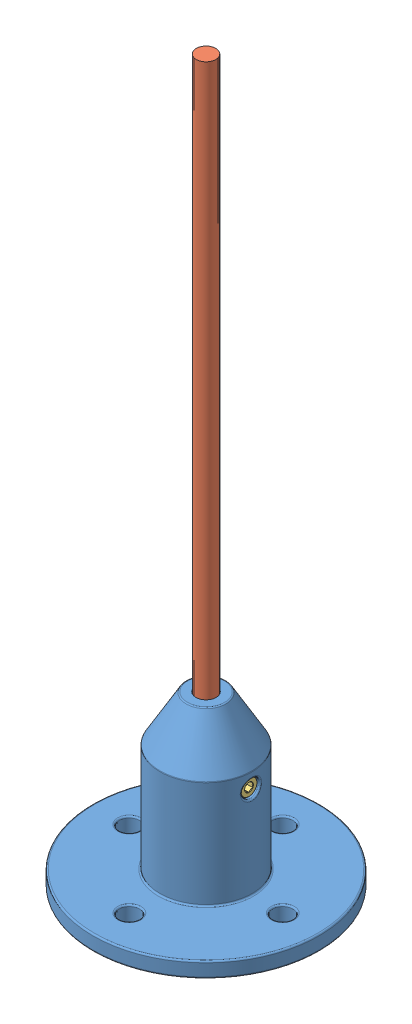
SolidWorks assembly Assem1, configuration Default. Lengths in mm.
Overall size (73.75 235 73.75).
6 component instances, 4 part files, 10 mates.
Components (placement in the parent):
- PNPush_0101_Mount-1: PNPush_0101_Mount [Default] at (24.8836 8.2043 78.5788) size (73.75 55 73.75)
- PNPush_0102_Stick-1: PNPush_0102_Stick [Default] at (24.8836 13.2043 78.5788) size (6.35 230 6.35)
- PNPush_0103_M3x8mm_Cap_Screw_(91290A113)-1: PNPush_0103_M3x8mm_Cap_Screw_(91290A113) [91290A113] at (27.8836 43.2043 78.5788) x (0 0 1) z (-1 0 0) size (5.5 5.5 11.2)
- PNPush_0103_M3x8mm_Cap_Screw_(91290A113)-2: PNPush_0103_M3x8mm_Cap_Screw_(91290A113) [91290A113] at (22.2855 43.2043 80.0788) x (-0.5 0 -0.866025) z (0.866025 0 -0.5) size (5.5 5.5 11.2)
- PNPush_0104_M3_Hex_Nut_(90591A250)-1: PNPush_0104_M3_Hex_Nut_(90591A250) [90591A250] at (30.7036 43.2043 78.5788) x (0 0 1) z (-1 0 0) size (5.5 6.35 2.78)
- PNPush_0104_M3_Hex_Nut_(90591A250)-2: PNPush_0104_M3_Hex_Nut_(90591A250) [90591A250] at (19.8433 43.2043 81.4888) x (-0.5 0 -0.866025) z (0.866025 0 -0.5) size (5.5 6.35 2.78)
Mates (geometry in assembly coordinates):
- Coincident1: coincident anti-aligned: plane of PNPush_0101_Mount-1 through (24.8836 13.2043 78.5788) normal (0 1 0); plane of PNPush_0102_Stick-1 through (24.8836 13.2043 78.5788) normal (0 -1 0)
- Concentric1: concentric aligned: cylinder of PNPush_0101_Mount-1 through (24.8836 63.2043 78.5788) axis (0 -1 0) radius 3.3; cylinder of PNPush_0102_Stick-1 through (24.8836 243.2043 78.5788) axis (0 -1 0) radius 3.175
- Coincident2: coincident: plane of PNPush_0101_Mount-1 through (29.5036 8.2043 78.5788) normal (1 0 0); plane of PNPush_0104_M3_Hex_Nut_(90591A250)-1 through (29.5036 43.3542 87.2437) normal (-1 0 0)
- Coincident3: coincident: plane of PNPush_0101_Mount-1 through (20.8825 8.2043 80.8888) normal (-0.866025 0 0.5); plane of PNPush_0104_M3_Hex_Nut_(90591A250)-2 through (14.7153 45.9733 70.2068) normal (0.866025 0 -0.5)
- Concentric2: concentric anti-aligned: circle of PNPush_0101_Mount-1; circle of PNPush_0104_M3_Hex_Nut_(90591A250)-2
- Concentric3: concentric anti-aligned: circle of PNPush_0101_Mount-1; circle of PNPush_0104_M3_Hex_Nut_(90591A250)-1
- Coincident4: coincident: plane of PNPush_0101_Mount-1 through (15.3573 43.2043 84.0788) normal (-0.866025 0 0.5); plane of PNPush_0103_M3x8mm_Cap_Screw_(91290A113)-2 through (15.3573 43.2043 84.0788) normal (0.866025 0 -0.5)
- Concentric4: concentric aligned: cylinder of PNPush_0101_Mount-1 through (-18.74 43.2043 103.7649) axis (0.866025 0 -0.5) radius 2.85; cylinder of PNPush_0103_M3x8mm_Cap_Screw_(91290A113)-2 through (12.7592 43.2043 85.5788) axis (0.866025 0 -0.5) radius 2.75
- Concentric5: concentric: cylinder of PNPush_0101_Mount-1 through (61.7586 43.2043 78.5788) axis (-1 0 0) radius 2.85; cylinder of PNPush_0103_M3x8mm_Cap_Screw_(91290A113)-1 through (38.8836 43.2043 78.5788) axis (-1 0 0) radius 2.75
- Coincident5: coincident anti-aligned: plane of PNPush_0101_Mount-1 through (35.8836 43.2043 78.5788) normal (1 0 0); plane of PNPush_0103_M3x8mm_Cap_Screw_(91290A113)-1 through (35.8836 43.2043 78.5788) normal (-1 0 0)
